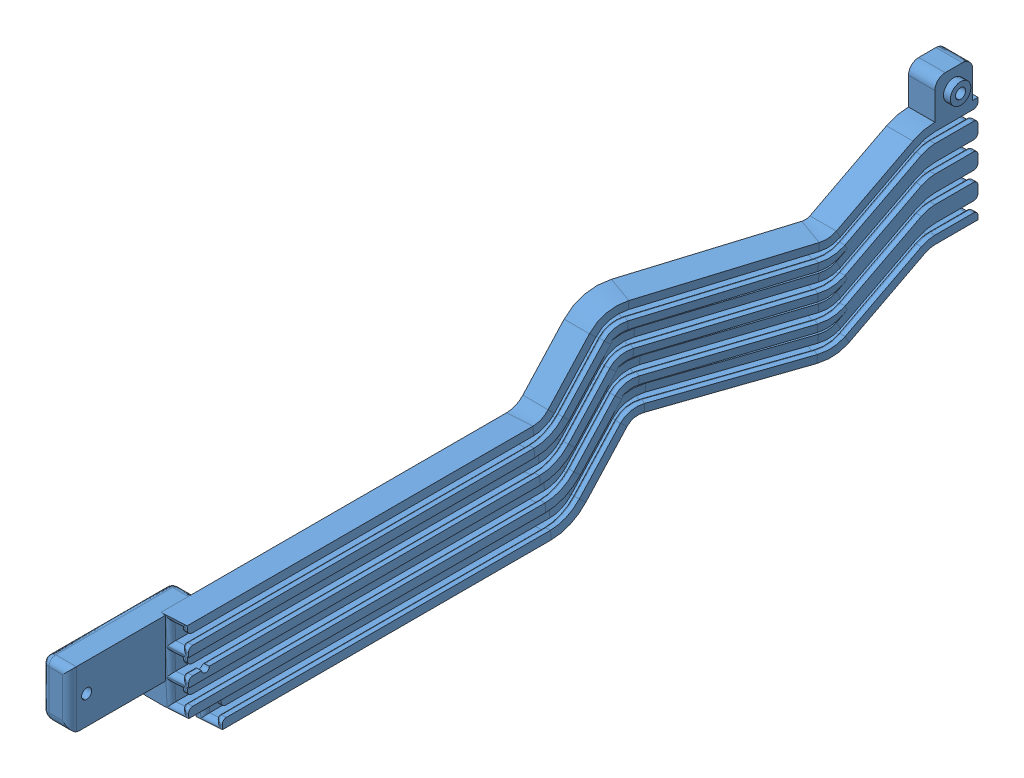
SolidWorks assembly cSL cap guide S2, configuration Default. Lengths in mm.
Overall size (31.83 76.05 242.8).
5 component instances, 2 part files, 4 mates.
Components (placement in the parent):
- cSL cap guides-1: cSL cap guides [21] at origin size (23.22 41.92 214.8) (hidden)
- cSL cap guides-2: cSL cap guides [22] at origin size (23.23 41.93 214.8) (hidden)
- cSL cap guides-3: cSL cap guides [23] at origin size (23.24 41.94 214.8) (hidden)
- cSL cap guides-4: cSL cap guides [24] at origin size (23.24 41.95 205) (hidden)
- cSL cap guide S2^cSL cap guide S2-1: cSL cap guide S2^cSL cap guide S2 [Default] at (-20.2 0 0) x (0 0 -1) z (1 0 0) size (242.8 76.05 31.83) (virtual)
Mates (geometry in assembly coordinates):
- InPlace1: in place: plane of ? through (-20.2 125.9 -652.4384) normal (1 0 0); plane of cSL cap guide S2^cSL cap guide S2-1 through (-20.2 0 0) normal (1 0 0); moOrthogonalPlaneRef_w of ? through (-20.2 125.9 -652.4384) normal (1 0 0); line of cSL cap guide S2^cSL cap guide S2-1 through (-55 -20.2 0) axis (0 0 1); plane of ? through (-20.2 125.9 -652.4384) normal (1 0 0); plane of cSL cap guide S2^cSL cap guide S2-1 through (-20.2 0 0) normal (0 0 -1); plane of ? through (-20.2 125.9 -652.4384) normal (1 0 0); unknown of cSL cap guide S2^cSL cap guide S2-1
- Coincident1: coincident aligned: plane of cSL cap guides-2; plane of cSL cap guide S2^cSL cap guide S2-1
- Coincident2: coincident aligned: moOrthogonalPlaneRef_w of cSL cap guides-2 through (-20.2 0 0) normal (0 1 0); plane of cSL cap guide S2^cSL cap guide S2-1
- Coincident3: coincident anti-aligned: moOrthogonalPlaneRef_w of cSL cap guides-2 through (-20.2 0 0) normal (0 0 1); plane of cSL cap guide S2^cSL cap guide S2-1 through (-20.2 0 0) normal (0 0 -1)
